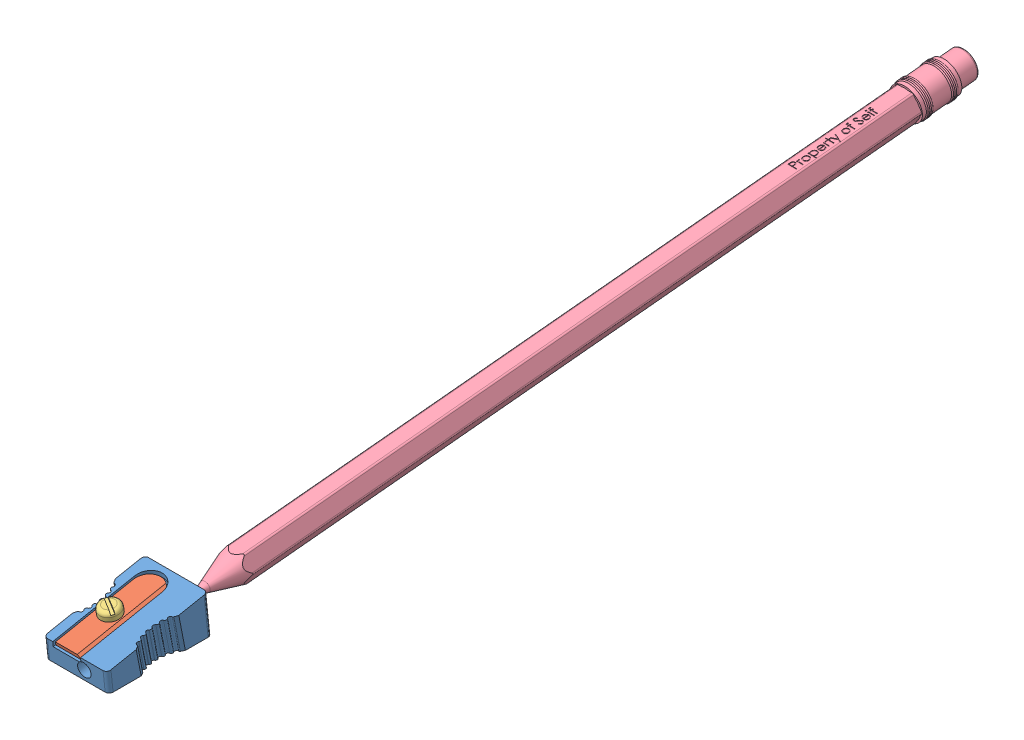
SolidWorks assembly Practice Model - Sharpener, configuration Default. Lengths in mm.
Overall size (16 28.32 223.06).
4 component instances, 4 part files, 5 mates.
Components (placement in the parent):
- Practice Model - Sharpener-1: Practice Model - Sharpener [Default] at (-39.9702 -4.4414 20.4679) size (16 9.95 26.52)
- Practice model - Sharpener Blade-1: Practice model - Sharpener Blade [Default] at (-38.5702 -0.5518 33.2757) x (1 0 0) z (0 -0.191744 0.981445) size (6.7 0.8 23.5)
- pan slot head_am-1: pan slot head_am [B18.6.7M - M2.5 x 0.45 x 5 Slotted PHMS --5N] at (-42.8702 4.4803 22.6433) x (0 -0.981445 -0.191744) z (0.866025 -0.095872 0.490722) size (7.16 5 5)
- Practice model - pencil-1: Practice model - pencil [Default] at (-37.9702 0.7798 5.4446) x (0.011383 0.995293 0.096237) z (-0.999935 0.01133 0.001096) size (8.6 195 8.6)
Mates (geometry in assembly coordinates):
- ProfileCenter2: profile center aligned: circle of Practice model - Sharpener Blade-1; circle of Practice Model - Sharpener-1
- Parallel3: parallel anti-aligned: line of Practice Model - Sharpener-1 through (-45.6702 4.5691 13.3227) axis (0 -0.191744 0.981445); line of Practice model - Sharpener Blade-1 through (-45.5702 0.2334 33.4291) axis (0 0.191744 -0.981445)
- Concentric3: concentric aligned: cylinder of Practice model - Sharpener Blade-1 through (-42.8702 2.4192 22.2406) axis (0 0.981445 0.191744) radius 1.4; cylinder of pan slot head_am-1 through (-42.8702 29.409 27.5136) axis (0 0.981445 0.191744) radius 2.5
- Coincident4: coincident anti-aligned: plane of Practice model - Sharpener Blade-1 through (-38.5702 0.2334 33.4291) normal (0 0.981445 0.191744); plane of pan slot head_am-1 through (-42.2452 2.6268 21.1782) normal (0 -0.981445 -0.191744)
- Concentric7: concentric aligned: cone of Practice Model - Sharpener-1 through (-37.9702 -2.0526 34.7379) axis (0 -0.096243 0.995358); cone of Practice model - pencil-1 through (-37.9702 0.7798 5.4446) axis (0 -0.096243 0.995358)
